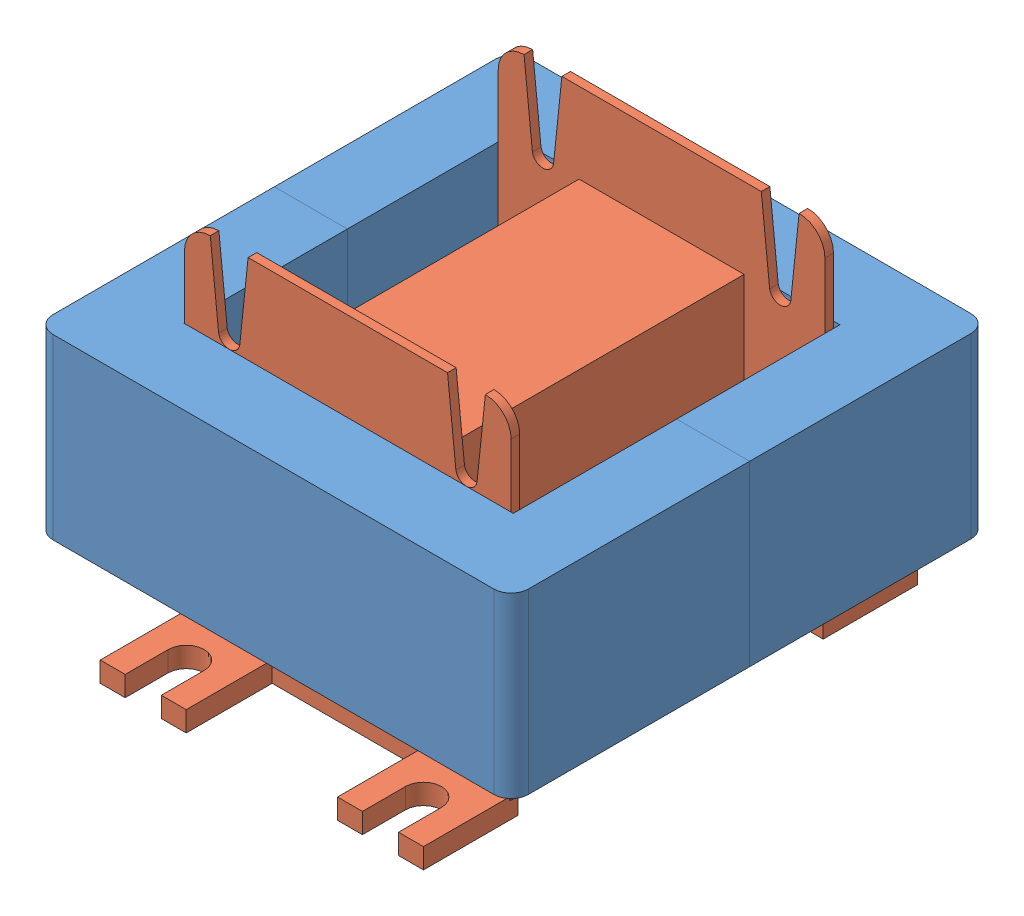
SolidWorks assembly transformer, configuration Default. Lengths in mm.
Overall size (55.3 41.5 57.5).
3 component instances, 2 part files, 6 mates.
Components (placement in the parent):
- e-core_tdk_7723z-1: e-core_tdk_7723z [Default] at (-29.1806 -6.8705 20.066) size (55.3 20.7 27.75)
- e-core_tdk_7723z-2: e-core_tdk_7723z [Default] at (26.1194 -6.8705 -35.434) x (-1 0 0) z (0 0 -1) size (55.3 20.7 27.75)
- bobbin2_tdk_7723z-1: bobbin2_tdk_7723z [Default] at (-1.6306 3.4295 -26.184) x (1 0 0) z (0 -1 0) size (38 57.5 41.5)
Mates (geometry in assembly coordinates):
- Coincident1: coincident anti-aligned: plane of e-core_tdk_7723z-1 through (-10.0306 13.8295 -7.684) normal (0 0 -1); plane of e-core_tdk_7723z-2 through (6.9694 13.8295 -7.684) normal (0 0 1)
- Coincident2: coincident aligned: plane of e-core_tdk_7723z-1 through (26.1194 13.8295 -7.684) normal (1 0 0); plane of e-core_tdk_7723z-2 through (26.1194 13.8295 -33.434) normal (1 0 0)
- Coincident3: coincident aligned: plane of e-core_tdk_7723z-1 through (24.1194 13.8295 18.066) normal (0 1 0); plane of e-core_tdk_7723z-2 through (-27.1806 13.8295 -33.434) normal (0 1 0)
- Coincident7: coincident anti-aligned: plane of e-core_tdk_7723z-1 through (24.1194 13.8295 18.066) normal (0 1 0); plane of bobbin2_tdk_7723z-1 through (-10.2306 13.8295 -25.184) normal (0 -1 0)
- Coincident8: coincident anti-aligned: plane of e-core_tdk_7723z-1 through (6.9694 13.8295 -7.684) normal (1 0 0); plane of bobbin2_tdk_7723z-1 through (6.9694 -6.9705 -25.184) normal (-1 0 0)
- Coincident9: coincident anti-aligned: plane of e-core_tdk_7723z-1 through (6.9694 13.8295 11.316) normal (0 0 -1); plane of bobbin2_tdk_7723z-1 through (-17.6306 21.1795 11.316) normal (0 0 1)
